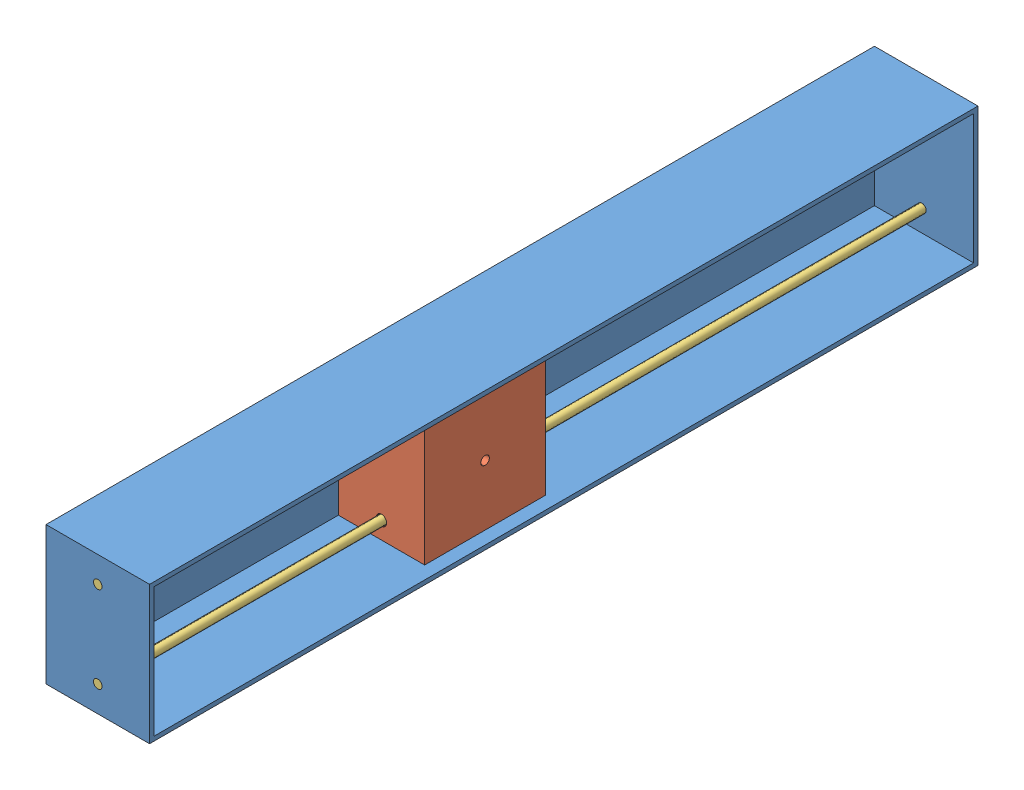
SolidWorks assembly w9-BoxAssembly, configuration Default. Lengths in mm.
4 component instances, 3 part files, 7 mates.
Components (placement in the parent):
- BoxFrame-1: BoxFrame [Default] at origin size (76.2 101.6 609.6)
- BoxStage-1: BoxStage [Default] at (-31.75 0 51.5811) size (63.5 88.9 88.9)
- BoxRod-1: BoxRod [Default] at (0 31.75 -304.8) size (6.35 6.35 609.6)
- BoxRod-2: BoxRod [Default] at (0 -31.75 -304.8) size (6.35 6.35 609.6)
Mates (geometry in assembly coordinates):
- Width1: width anti-aligned: plane of BoxFrame-1 through (38.1 47.625 -304.8) normal (0 -1 0); plane of BoxFrame-1 through (38.1 -47.625 -304.8) normal (0 1 0); plane of BoxStage-1 through (31.75 44.45 96.0311) normal (0 1 0); plane of BoxStage-1 through (31.75 -44.45 96.0311) normal (0 -1 0)
- Concentric1: concentric anti-aligned: circle of BoxStage-1; cylinder of BoxRod-1 through (0 31.75 304.8) axis (0 0 -1) radius 3.175
- Coincident3: coincident aligned: plane of BoxFrame-1 through (38.1 50.8 -304.8) normal (0 0 -1); plane of BoxRod-1 through (0 31.75 -304.8) normal (0 0 -1)
- Concentric2: concentric anti-aligned: cylinder of BoxStage-1 through (0 -31.75 7.1311) axis (0 0 1) radius 3.81; cylinder of BoxRod-2 through (0 -31.75 304.8) axis (0 0 -1) radius 3.175
- Coincident4: coincident aligned: plane of BoxFrame-1 through (38.1 50.8 -304.8) normal (0 0 -1); plane of BoxRod-2 through (0 -31.75 -304.8) normal (0 0 -1)
- LimitDistance1: limit distance = 308.7561 mm anti-aligned: plane of BoxFrame-1 through (38.1 50.8 -301.625) normal (0 0 1); plane of BoxStage-1 through (31.75 44.45 7.1311) normal (0 0 -1)
- Concentric3: concentric anti-aligned: cylinder of BoxFrame-1 through (0 31.75 -304.8) axis (0 0 1) radius 3.175; cylinder of BoxRod-1 through (0 31.75 304.8) axis (0 0 -1) radius 3.175
